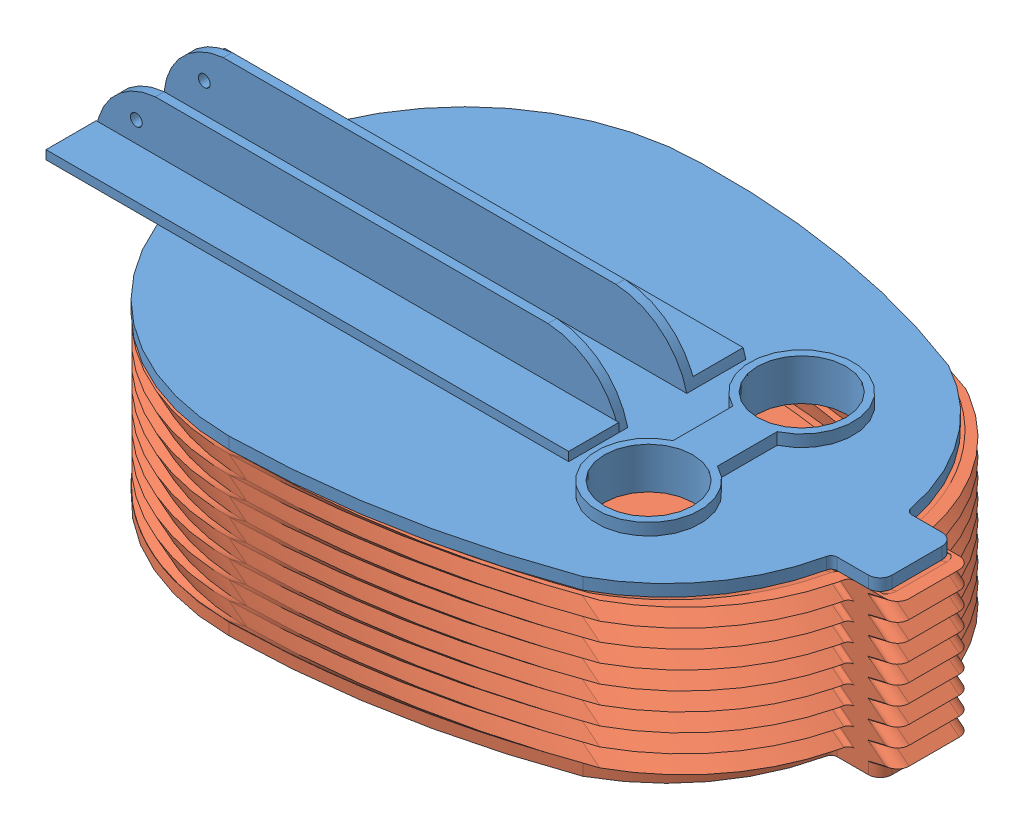
SolidWorks assembly Assem fuelle2, configuration Default. Lengths in mm.
Overall size (270.82 78.6 167.56).
2 component instances, 2 part files, 4 mates.
Components (placement in the parent):
- tapa sup de fuelle-1: tapa sup de fuelle [Default] at (-44.8851 4.2436 7.1123) size (265 43.89 160.08)
- tapa de fuelle-2: tapa de fuelle [Default] at (-44.8851 -50.3326 7.1123) size (241.61 58.4 167.56)
Mates (geometry in assembly coordinates):
- Coincident1: coincident: plane of ? through (106.622 -24.7432 -8.6799) normal (1 0 0); plane of tapa sup de fuelle-1 through (106.622 44.2489 -8.6799) normal (1 0 0)
- Coincident2: coincident: plane of ? through (102.622 -24.7432 12.3201) normal (0 0 1); plane of tapa sup de fuelle-1 through (102.622 44.2489 12.3201) normal (0 0 1)
- Coincident3: coincident: plane of tapa sup de fuelle-1 through (80.1149 8.2436 -1.3877) normal (1 0 0); plane of tapa de fuelle-2 through (80.1149 -46.3326 -1.3877) normal (1 0 0)
- Coincident4: coincident: plane of tapa sup de fuelle-1 through (76.1149 8.2436 19.6123) normal (0 0 1); plane of tapa de fuelle-2 through (76.1149 -46.3326 19.6123) normal (0 0 1)
